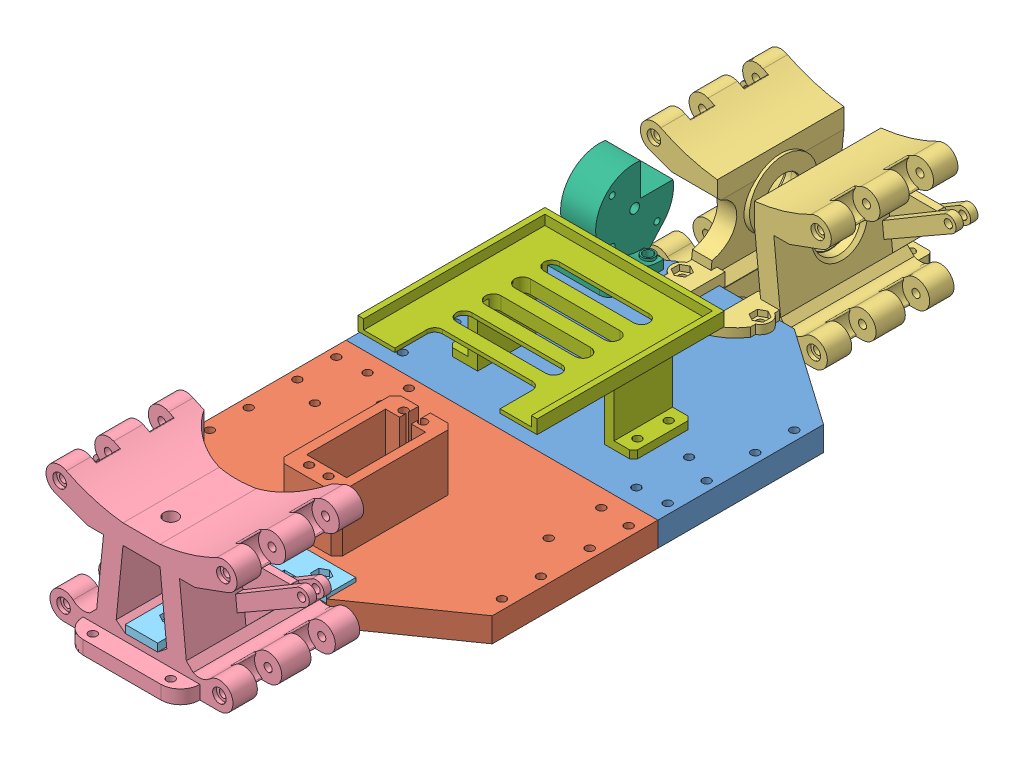
SolidWorks assembly Assem3, configuration Default. Lengths in mm.
Overall size (160 68.56 390).
7 component instances, 7 part files, 18 mates.
Components (placement in the parent):
- BB_Base-1: BB_Base [Default] at (31.0073 63.2426 186.1824) x (-1 0 0) z (0 0 -1) size (160 12.5 120)
- FF_Base-1: FF_Base [Default] at (31.0073 63.2426 271.1824) size (160 41.5 120)
- BBDrive_BaseV82-1: BBDrive_BaseV82 [Default] at (31.0073 63.2396 43.6824) size (118.58 68.56 102.04)
- FFDrive_BaseV2-1: FFDrive_BaseV2 [Default] at (31.0073 63.2426 348.6824) size (118.58 68.56 76.42)
- FFBody_to_Drive-1: FFBody_to_Drive [Default] at (-8.4411 73.7426 66.322) size (60 4 80)
- MoterV3-1: MoterV3 [Default] at (-17.8202 75.7426 3.3906) x (1 0 0) z (0 1 0) size (37.37 43.05 44.5)
- Pi5_coverB-1: Pi5_coverB [Default] at (31.0373 93.2426 178.6824) size (95 42 96)
Mates (geometry in assembly coordinates):
- Coincident1: coincident anti-aligned: line of BB_Base-1 through (-48.9927 75.7426 228.6824) axis (1 0 0); line of FF_Base-1 through (111.0073 75.7426 228.6824) axis (-1 0 0)
- Coincident2: coincident aligned: line of BB_Base-1 through (111.0073 75.7426 228.6824) axis (0 0 -1); line of FF_Base-1 through (111.0073 75.7426 313.6824) axis (0 0 -1)
- Concentric1: concentric anti-aligned: cylinder of BB_Base-1 through (51.0073 59.047 116.1824) axis (0 1 0) radius 2.1; cylinder of BBDrive_BaseV82-1 through (51.0073 88.2396 116.1824) axis (0 -1 0) radius 2.1
- Concentric2: concentric anti-aligned: cylinder of BB_Base-1 through (11.0073 59.047 116.1824) axis (0 1 0) radius 2.1; cylinder of BBDrive_BaseV82-1 through (11.0073 88.2396 116.1824) axis (0 -1 0) radius 2.1
- Coincident3: coincident anti-aligned: plane of BB_Base-1 through (31.0073 75.7426 186.1824) normal (0 1 0); plane of BBDrive_BaseV82-1 through (31.0073 75.7426 123.6824) normal (0 -1 0)
- Coincident4: coincident anti-aligned: line of FF_Base-1 through (1.0073 73.7426 348.6824) axis (1 0 0); line of FFDrive_BaseV2-1 through (39.3016 73.7426 348.6824) axis (-1 0 0)
- Coincident5: coincident aligned: cylinder of FF_Base-1 through (11.0073 59.047 341.1824) axis (0 1 0) radius 2.1; circle of FFBody_to_Drive-1
- Concentric3: concentric anti-aligned: cylinder of FF_Base-1 through (51.0073 59.047 341.1824) axis (0 1 0) radius 2.1; cylinder of FFBody_to_Drive-1 through (51.0073 77.7426 341.1824) axis (0 -1 0) radius 2.1
- Coincident6: coincident anti-aligned: cylinder of FFDrive_BaseV2-1 through (31.0073 48.7426 398.6824) axis (0 1 0) radius 2.1; circle of FFBody_to_Drive-1
- Coincident7: coincident anti-aligned: plane of FF_Base-1 through (31.0073 73.7426 271.1824) normal (0 1 0); plane of FFBody_to_Drive-1 through (-8.4411 73.7426 66.322) normal (0 -1 0)
- Concentric4: concentric anti-aligned: cylinder of BB_Base-1 through (-3.9927 37.7426 138.6824) axis (0 1 0) radius 2.1; cylinder of MoterV3-1 through (-3.9927 80.2426 138.6824) axis (0 -1 0) radius 2.1
- Concentric5: concentric anti-aligned: cylinder of BB_Base-1 through (-28.9927 37.7426 138.6824) axis (0 1 0) radius 2.1; cylinder of MoterV3-1 through (-28.9927 80.2426 138.6824) axis (0 -1 0) radius 2.1
- Concentric6: concentric anti-aligned: cylinder of BB_Base-1 through (-3.9927 37.7426 118.6824) axis (0 1 0) radius 2.1; cylinder of MoterV3-1 through (-3.9927 81.7426 118.6824) axis (0 -1 0) radius 2.5
- Coincident8: coincident anti-aligned: plane of BB_Base-1 through (31.0073 75.7426 186.1824) normal (0 1 0); plane of MoterV3-1 through (-17.8202 75.7426 3.3906) normal (0 -1 0)
- Concentric7: concentric aligned: cylinder of BB_Base-1 through (73.5373 37.7426 185.6824) axis (0 1 0) radius 2.1; cylinder of Pi5_coverB-1 through (73.5373 69.8029 185.6824) axis (0 1 0) radius 2.1
- Concentric8: concentric aligned: cylinder of BB_Base-1 through (73.5373 37.7426 201.6824) axis (0 1 0) radius 2.1; cylinder of Pi5_coverB-1 through (73.5373 69.8029 201.6824) axis (0 1 0) radius 2.1
- Parallel1: parallel aligned: cylinder of BB_Base-1 through (-11.5227 37.7426 185.6824) axis (0 1 0) radius 2.1; cylinder of Pi5_coverB-1 through (-11.4627 69.8029 185.6824) axis (0 1 0) radius 2.1
- Parallel2: parallel aligned: cylinder of BB_Base-1 through (-11.5227 37.7426 201.6824) axis (0 1 0) radius 2.1; cylinder of Pi5_coverB-1 through (-11.4627 69.8029 201.6824) axis (0 1 0) radius 2.1
